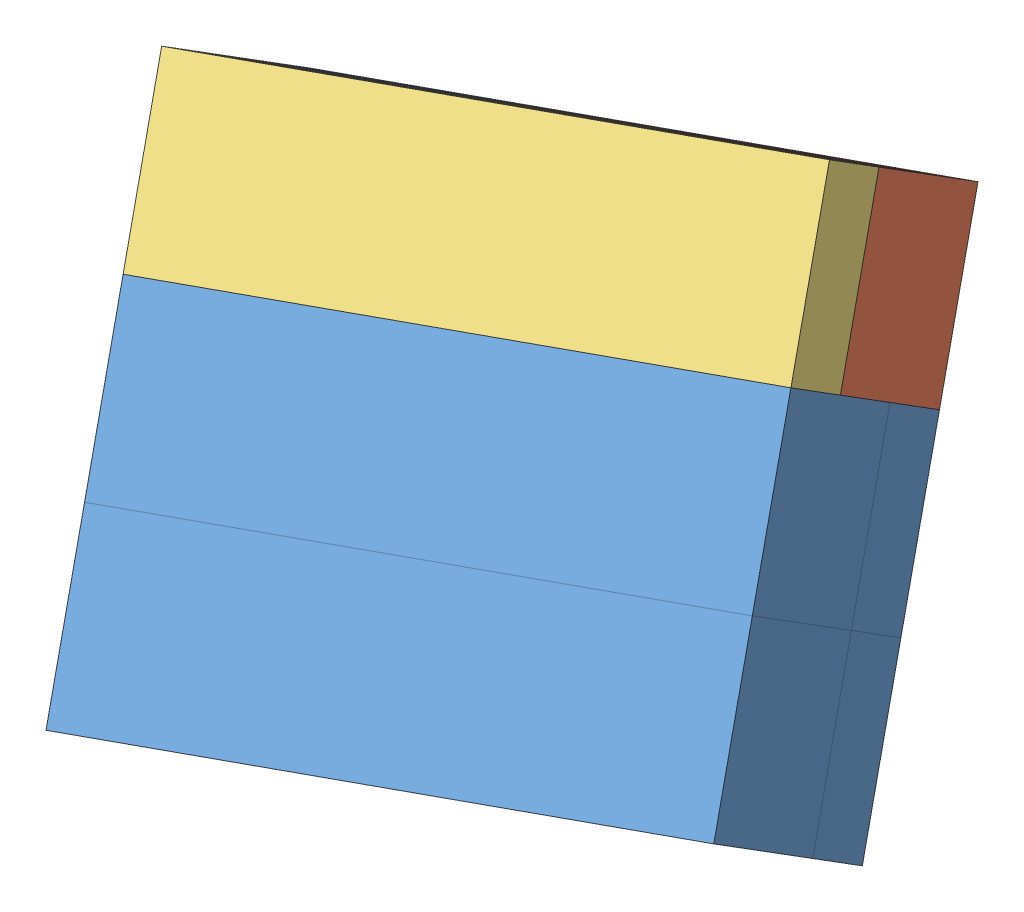
SolidWorks assembly Assembly 1, configuration Default. Lengths in mm.
Overall size (139.83 126.54 153.78).
7 component instances, 4 part files, 23 mates.
Components (placement in the parent):
- hw1.3-1: hw1.3 [Default] at (85.1672 91.475 239.2625) x (0.872349 -0.008808 -0.488804) z (-0.281961 0.807726 -0.517761) size (90 60 30)
- hw1.1-1: hw1.1 [Default] at (19.22 87.0164 152.3367) x (-0.872349 0.008808 0.488804) z (-0.281961 0.807726 -0.517761) size (60 60 30)
- hw1.2-1: hw1.2 [Default] at (50.5378 115.971 238.3938) x (-0.872349 0.008808 0.488804) z (0.281961 -0.807726 0.517761) size (90 60 30)
- hw1.4-1: hw1.4 [Default] at (60.1005 73.9223 225.5305) x (-0.281961 0.807726 -0.517761) z (0.39938 0.589492 0.702136) size (90 60 30)
- hw1.3-2: hw1.3 [Default] at (-3.118 38.9492 205.3985) x (-0.872349 0.008808 0.488804) z (-0.281961 0.807726 -0.517761) size (90 60 30)
- hw1.3-3: hw1.3 [Default] at (76.7083 115.7067 223.7296) x (0.872349 -0.008808 -0.488804) z (-0.281961 0.807726 -0.517761) size (90 60 30)
- hw1.3-4: hw1.3 [Default] at (-3.118 38.9492 205.3985) x (-0.872349 0.008808 0.488804) z (-0.39938 -0.589492 -0.702136) size (90 60 30)
Mates (geometry in assembly coordinates):
- Coincident1: coincident anti-aligned: plane of hw1.3-1 through (68.5594 49.6905 241.0633) normal (-0.39938 -0.589492 -0.702136); plane of hw1.3-2 through (16.2184 50.219 270.3915) normal (0.39938 0.589492 0.702136)
- Coincident2: coincident anti-aligned: plane of hw1.3-1 through (82.7484 31.7415 205.3351) normal (-0.39938 -0.589492 -0.702136); plane of hw1.3-2 through (30.4075 32.27 234.6633) normal (0.39938 0.589492 0.702136)
- Coincident3: coincident anti-aligned: line of hw1.3-1 through (74.2896 55.9733 189.8023) axis (-0.872349 0.008808 0.488804); line of hw1.3-2 through (21.9486 56.5018 219.1305) axis (0.872349 -0.008808 -0.488804)
- Coincident4: coincident aligned: line of hw1.3-1 through (7.7596 74.4508 254.8587) axis (0.39938 0.589492 0.702136); line of hw1.3-2 through (-16.2033 39.0813 212.7305) axis (0.39938 0.589492 0.702136)
- Coincident5: coincident anti-aligned: line of hw1.3-3 through (65.8308 80.2051 174.2694) axis (-0.872349 0.008808 0.488804); line of hw1.3-4 through (13.4898 80.7336 203.5977) axis (0.872349 -0.008808 -0.488804)
- Coincident7: coincident anti-aligned: plane of hw1.4-1 through (56.578 32.0058 219.9992) normal (0.872349 -0.008808 -0.488804); plane of hw1.3-3 through (48.1191 56.2376 204.4664) normal (-0.872349 0.008808 0.488804)
- Coincident8: coincident anti-aligned: plane of hw1.4-1 through (48.1191 56.2376 204.4664) normal (-0.39938 -0.589492 -0.702136); plane of hw1.3-4 through (8.8634 56.6339 226.4626) normal (0.39938 0.589492 0.702136)
- Coincident9: coincident anti-aligned: line of hw1.4-1 through (5.031 104.9654 188.0648) axis (-0.872349 0.008808 0.488804); line of hw1.3-4 through (-21.1395 105.2296 202.729) axis (0.872349 -0.008808 -0.488804)
- Coincident10: coincident aligned: line of hw1.3-3 through (98.2524 91.3428 231.9304) axis (-0.39938 -0.589492 -0.702136); line of hw1.3-4 through (74.2896 55.9733 189.8023) axis (-0.39938 -0.589492 -0.702136)
- Coincident11: coincident aligned: line of hw1.3-3 through (7.7596 74.4508 254.8587) axis (0.39938 0.589492 0.702136); line of hw1.4-1 through (-4.2218 56.7661 233.7946) axis (0.39938 0.589492 0.702136)
- Coincident12: coincident anti-aligned: line of hw1.4-1 through (-9.1581 122.9144 223.793) axis (0.281961 -0.807726 0.517761); line of hw1.3-3 through (7.7596 74.4508 254.8587) axis (-0.281961 0.807726 -0.517761)
- Coincident13: coincident aligned: line of hw1.3-1 through (16.2184 50.219 270.3915) axis (0.39938 0.589492 0.702136); line of hw1.3-2 through (-7.7444 14.8495 228.2634) axis (0.39938 0.589492 0.702136)
- Coincident14: coincident anti-aligned: line of hw1.3-1 through (60.1005 73.9223 225.5305) axis (-0.872349 0.008808 0.488804); line of hw1.3-2 through (7.7596 74.4508 254.8587) axis (0.872349 -0.008808 -0.488804)
- Coincident15: coincident aligned: plane of hw1.4-1 through (30.4075 32.27 234.6633) normal (0.281961 -0.807726 0.517761); plane of hw1.3-2 through (5.3408 14.7174 220.9313) normal (0.281961 -0.807726 0.517761)
- Coincident16: coincident anti-aligned: line of hw1.4-1 through (30.4075 32.27 234.6633) axis (0.39938 0.589492 0.702136); line of hw1.3-2 through (42.3889 49.9548 255.7274) axis (-0.39938 -0.589492 -0.702136)
- Coincident17: coincident aligned: line of hw1.4-1 through (30.4075 32.27 234.6633) axis (0.872349 -0.008808 -0.488804); line of hw1.3-2 through (30.4075 32.27 234.6633) axis (0.872349 -0.008808 -0.488804)
- Coincident18: coincident anti-aligned: plane of hw1.1-1 through (13.4898 80.7336 203.5977) normal (0.39938 0.589492 0.702136); plane of hw1.2-1 through (5.031 104.9654 188.0648) normal (-0.39938 -0.589492 -0.702136)
- Coincident19: coincident anti-aligned: plane of hw1.1-1 through (51.6417 98.1541 209.9976) normal (0.39938 0.589492 0.702136); plane of hw1.2-1 through (43.1828 122.3859 194.4648) normal (-0.39938 -0.589492 -0.702136)
- Coincident20: coincident aligned: line of hw1.1-1 through (43.1828 122.3859 194.4648) axis (0.872349 -0.008808 -0.488804); line of hw1.2-1 through (43.1828 122.3859 194.4648) axis (0.872349 -0.008808 -0.488804)
- Coincident21: coincident aligned: line of hw1.1-1 through (5.031 104.9654 188.0648) axis (0.872349 -0.008808 -0.488804); line of hw1.2-1 through (5.031 104.9654 188.0648) axis (0.872349 -0.008808 -0.488804)
- Coincident22: coincident aligned: line of hw1.1-1 through (39.6603 80.4693 188.9336) axis (0.39938 0.589492 0.702136); line of hw1.2-1 through (39.6603 80.4693 188.9336) axis (0.39938 0.589492 0.702136)
- Coincident23: coincident anti-aligned: line of hw1.2-1 through (89.7936 115.5746 216.3976) axis (-0.872349 0.008808 0.488804); line of hw1.3-3 through (11.2821 116.3674 260.3899) axis (0.872349 -0.008808 -0.488804)
- Coincident24: coincident aligned: line of hw1.1-1 through (77.8122 97.8899 195.3335) axis (-0.39938 -0.589492 -0.702136); line of hw1.3-4 through (65.8308 80.2051 174.2694) axis (-0.39938 -0.589492 -0.702136)
